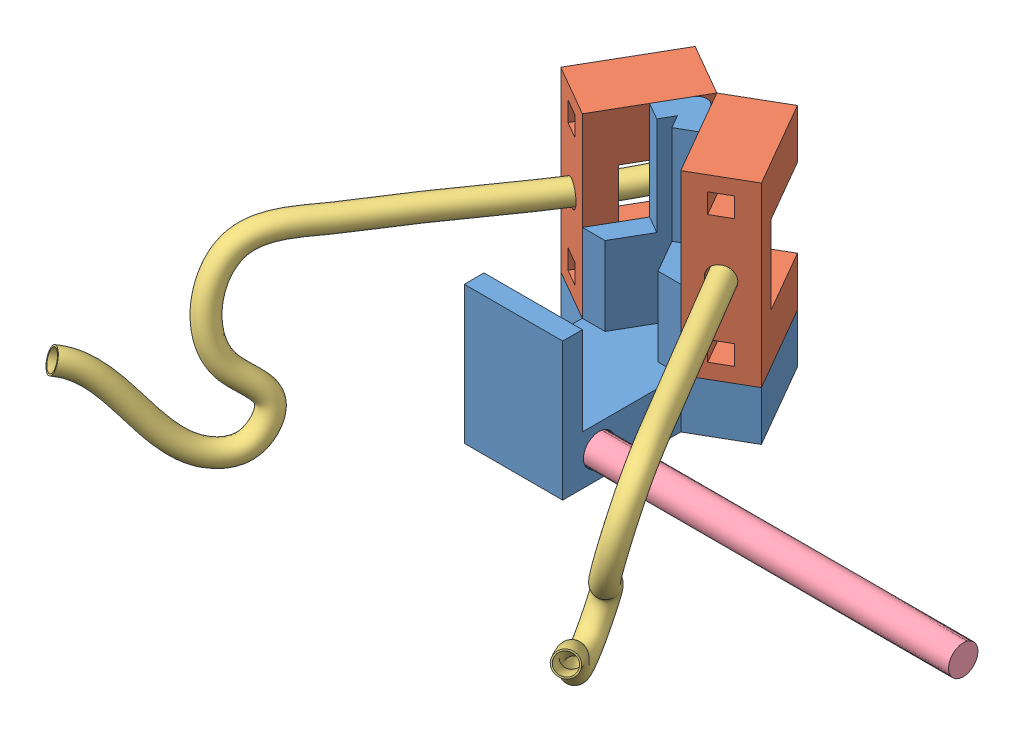
SolidWorks assembly Assem1, configuration Default. Lengths in mm.
Overall size (70 27.42 47.53).
6 component instances, 4 part files, 13 mates.
Components (placement in the parent):
- DividedDualPort-1: DividedDualPort [Default] at (20.4322 5.0695 16.9929) size (20.39 23 23.66)
- Sensor8mm-1: Sensor8mm [Default] at (14.1502 7.0695 16.9929) x (0 1 0) z (-0.5 0 -0.866025) size (18 6 10)
- Sensor8mm-2: Sensor8mm [Default] at (4.1502 25.0695 16.9929) x (0 -1 0) z (0.5 0 -0.866025) size (18 6 10)
- FeedingTube-1: FeedingTube [Default] at (13.0045 16.4383 8.8467) x (-0.836023 0.232966 0.496783) z (-0.507738 0.014769 -0.861385) size (2.3 19.62 45.71)
- FeedingTube-2: FeedingTube [Default] at (4.5972 16.0898 9.8231) x (-0.858116 -0.212246 -0.467534) z (0.486776 -0.046589 -0.872283) size (2.3 19.62 45.71)
- Rod-1: Rod [Default] at (11.1502 4.6695 25.2915) size (40 3 3)
Mates (geometry in assembly coordinates):
- Coincident1: coincident anti-aligned: plane of DividedDualPort-1 through (15.7207 25.0695 19.7131) normal (0.866025 0 -0.5); plane of Sensor8mm-1 through (14.1502 7.0695 16.9929) normal (-0.866025 0 0.5)
- Coincident2: coincident anti-aligned: plane of DividedDualPort-1 through (20.4322 7.0695 16.9929) normal (0 1 0); plane of Sensor8mm-1 through (14.3463 7.0695 5.3327) normal (0 -1 0)
- Coincident3: coincident anti-aligned: plane of DividedDualPort-1 through (8.2207 25.0695 9.9426) normal (-0.866025 0 -0.5); plane of Sensor8mm-2 through (4.1502 25.0695 16.9929) normal (0.866025 0 0.5)
- Coincident4: coincident anti-aligned: plane of DividedDualPort-1 through (20.4322 7.0695 16.9929) normal (0 1 0); plane of Sensor8mm-2 through (-1.046 7.0695 13.9929) normal (0 -1 0)
- Coincident5: coincident aligned: plane of DividedDualPort-1 through (19.3463 2.0695 13.9929) normal (0.5 0 0.866025); plane of Sensor8mm-1 through (19.3463 7.0695 13.9929) normal (0.5 0 0.866025)
- Coincident6: coincident aligned: plane of DividedDualPort-1 through (-1.046 2.0695 13.9929) normal (-0.5 0 0.866025); plane of Sensor8mm-2 through (-1.046 25.0695 13.9929) normal (-0.5 0 0.866025)
- Tangent4: tangent: circle of Sensor8mm-1; face of FeedingTube-1
- Tangent5: tangent: circle of Sensor8mm-1; face of FeedingTube-1
- Tangent6: tangent: circle of Sensor8mm-2; face of FeedingTube-2
- Tangent7: tangent: circle of Sensor8mm-2; face of FeedingTube-2
- Coincident7: coincident: plane of DividedDualPort-1 through (11.1502 4.6695 25.2915) normal (1 0 0); plane of Rod-1 through (11.1502 4.6695 25.2915) normal (-1 0 0)
- Concentric1: concentric: cylinder of DividedDualPort-1 through (11.1502 4.6695 25.2915) axis (1 0 0) radius 1.6; cylinder of Rod-1 through (51.1502 4.6695 25.2915) axis (-1 0 0) radius 1.5
- Lock1: lock: unknown of DividedDualPort-1; unknown of Rod-1
